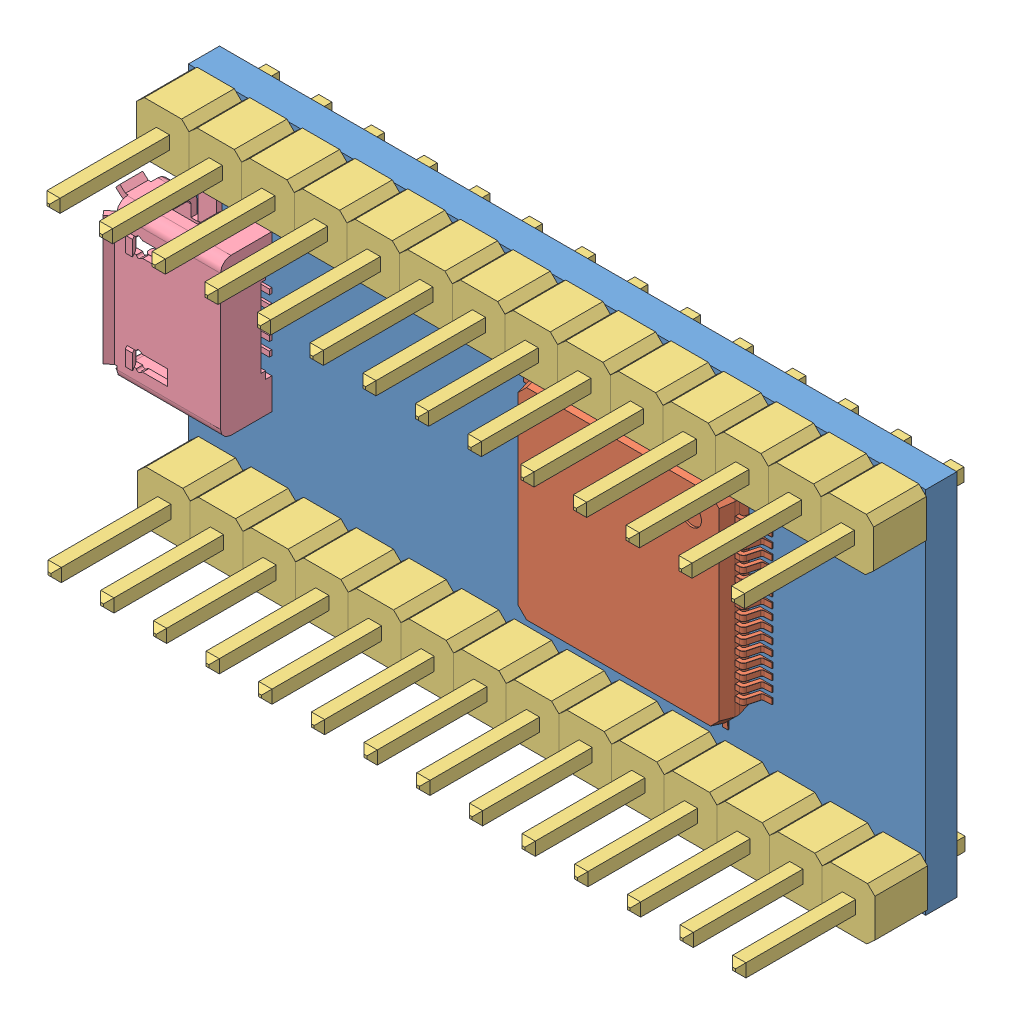
SolidWorks assembly Teensy 3.2 + header, configuration Default. Lengths in mm.
Overall size (37.22 17.93 11.07).
5 component instances, 4 part files, 5 mates.
Components (placement in the parent):
- Teensy 3.2 + header-1: Teensy 3.2 + header [Default] at origin size (35.56 17.78 1.5)
- LQFP64_Grid_0.5_LQFP64_Koerper_2-1: LQFP64_Grid_0.5_LQFP64_Koerper_2 [Default] at (4.4157 0.1275 1.35) x (-1 0 0) z (0 1 0) size (12 1.6 12)
- .100 Header-1: .100 Header [14] at (16.6183 -7.6966 1.5) x (0 -1 0) z (0 0 1) size (2.54 35.56 11.07)
- .100 Header-2: .100 Header [14] at (16.5569 7.6954 1.5) x (0 -1 0) z (0 0 1) size (2.54 35.56 11.07)
- Hirose Micro USB Digikey PN H11635CT-ND-2: Hirose Micro USB Digikey PN H11635CT-ND [Default] at (-19.3541 0.1395 2.74) x (0 -1 0) z (-1 0 0) size (8.8 3 5.6)
Mates (geometry in assembly coordinates):
- Coincident21: coincident anti-aligned: plane of Teensy 3.2 + header-1 through (0 0 1.5) normal (0 0 1); plane of LQFP64_Grid_0.5_LQFP64_Koerper_2-1 through (4.4157 -4.8725 1.5) normal (0 0 -1)
- Coincident31: coincident anti-aligned: plane of Teensy 3.2 + header-1 through (0 0 1.5) normal (0 0 1); plane of .100 Header-1 through (16.6183 -7.6966 1.5) normal (0 0 -1)
- Coincident41: coincident anti-aligned: plane of Teensy 3.2 + header-1 through (0 0 1.5) normal (0 0 1); plane of .100 Header-2 through (16.5569 7.6954 1.5) normal (0 0 -1)
- Coincident421: coincident anti-aligned: plane of Teensy 3.2 + header-1 through (0 0 1.5) normal (0 0 1); plane of Hirose Micro USB Digikey PN H11635CT-ND-2 through (-18.7541 3.3995 1.5) normal (0 0 -1)
- Parallel1: parallel anti-aligned: plane of Teensy 3.2 + header-1 through (-17.78 -8.89 1.5) normal (-1 0 0); plane of Hirose Micro USB Digikey PN H11635CT-ND-2 through (-13.7541 0.1395 2.74) normal (1 0 0)
